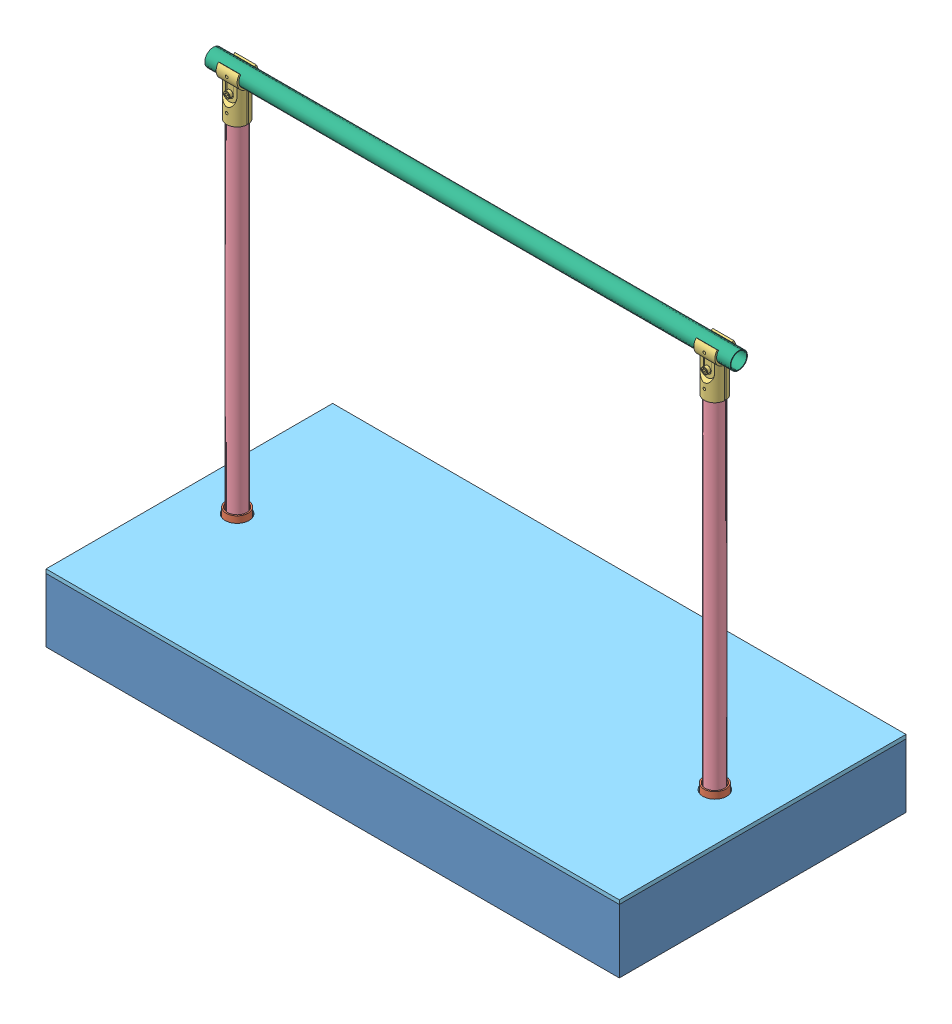
SolidWorks assembly 1000-Assembled, configuration Default. Lengths in mm.
Overall size (914.4 733.48 457.2).
13 component instances, 6 part files, 8 mates.
Components (placement in the parent):
- 1100-BaseAsm-1: 1100-BaseAsm [Default] at origin size (914.4 117.35 457.2)
  - 6001-Base-1: 6001-Base [Default] at origin size (914.4 101.6 457.2)
  - 6005-ClampFitting-4: 6005-ClampFitting [2534T82] at (838.2 0 -228.6) x (1 0 0) z (0 1 0) size (88.9 88.9 104.65)
  - 6005-ClampFitting-5: 6005-ClampFitting [2534T82] at (76.2 0 -228.6) x (1 0 0) z (0 1 0) size (88.9 88.9 104.65)
- 1120-Post-2: 1120-Post [Default] at (775.0772 -13.8338 11.1753) size (33.53 713.41 34.1)
  - 6015-ClampOpen-1: 6015-ClampOpen [2534T22] at (63.1228 720.8951 -239.7753) size (33.53 76.2 34.1)
  - 6010-PipeSide-3: 6010-PipeSide [2534T132] at (63.1228 348.0978 -239.7753) x (1 0 0) z (0 1 0) size (27.43 27.43 660.4)
- 6003-BaseTop-1: 6003-BaseTop [Default] at (0 88.9 0) size (914.4 6.35 457.2)
- 1120-Post-3: 1120-Post [Default] at (13.0772 -13.8338 11.1753) size (33.53 713.41 34.1)
  - 6015-ClampOpen-1: 6015-ClampOpen [2534T22] at (63.1228 720.8951 -239.7753) size (33.53 76.2 34.1)
  - 6010-PipeSide-3: 6010-PipeSide [2534T132] at (63.1228 348.0978 -239.7753) x (1 0 0) z (0 1 0) size (27.43 27.43 660.4)
- 1150-TopAsm-1: 1150-TopAsm [Default] at (1072.123 313.1357 -461.2468) x (0 0 1) z (-1 0 0) size (27.43 27.43 838.2)
  - 6020-PipeTop-1: 6020-PipeTop [2534T132] at (232.6468 393.9256 614.7602) size (27.43 27.43 838.2)
Mates (geometry in assembly coordinates):
- Coincident1: coincident aligned: plane of 1100-BaseAsm-1/6005-ClampFitting-4 through (838.2 4.064 -228.6) normal (0 1 0); circle of 1120-Post-2/6010-PipeSide-3
- Concentric1: concentric anti-aligned: cylinder of 1100-BaseAsm-1/6005-ClampFitting-4 through (838.2 104.648 -228.6) axis (0 -1 0) radius 17.526; circle of 1120-Post-2/6010-PipeSide-3
- Coincident2: coincident anti-aligned: plane of 1100-BaseAsm-1/6001-Base-1 through (0 88.9 0) normal (0 1 0); plane of 6003-BaseTop-1 through (0 88.9 0) normal (0 -1 0)
- Coincident3: coincident aligned: plane of 1100-BaseAsm-1/6001-Base-1 through (0 -12.7 0) normal (0 0 1); plane of 6003-BaseTop-1 through (0 95.25 0) normal (0 0 1)
- Coincident4: coincident aligned: plane of 1100-BaseAsm-1/6001-Base-1 through (0 -12.7 -457.2) normal (-1 0 0); plane of 6003-BaseTop-1 through (0 95.25 0) normal (-1 0 0)
- Concentric2: concentric aligned: circle of 1100-BaseAsm-1/6005-ClampFitting-5; circle of 1120-Post-3/6010-PipeSide-3
- Coincident5: coincident aligned: plane of 1100-BaseAsm-1/6005-ClampFitting-5 through (76.2 4.064 -228.6) normal (0 1 0); circle of 1120-Post-3/6010-PipeSide-3
- Concentric3: concentric anti-aligned: circle of 1120-Post-2/6015-ClampOpen-1; cylinder of 1150-TopAsm-1/6020-PipeTop-1 through (38.2628 707.0613 -228.6) axis (1 0 0) radius 13.716
